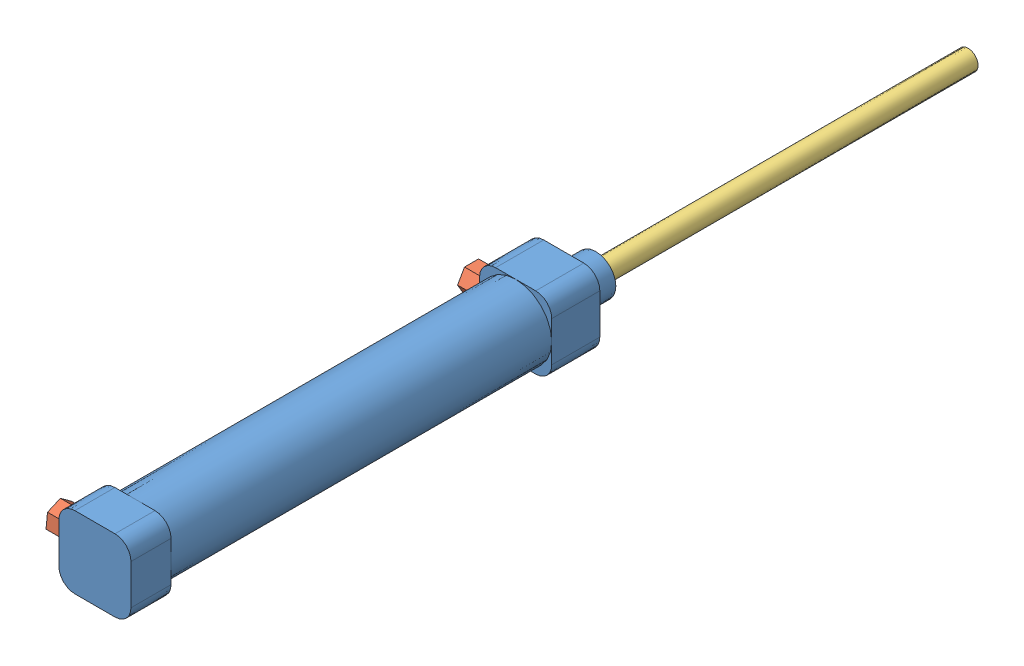
SolidWorks assembly 2气缸16-75（带铰链）装配体, configuration 默认. Lengths in mm.
Overall size (26.22 22.45 217.89).
4 component instances, 3 part files, 6 mates.
Components (placement in the parent):
- 222.4气缸16-75-1: 222.4气缸16-75 [默认] at (2.6982 -2.5413 -63) size (18 18 125)
- 222.4气缸嘴16-75-1: 222.4气缸嘴16-75 [默认] at (-3.3018 -2.5413 -67) x (0 0 1) z (-1 0 0) size (7 6.07 9)
- 222.4气缸杆16-75-1: 222.4气缸杆16-75 [默认] at (2.6982 -2.5413 -40.8909) x (-0.612502 -0.790469 0) z (0 0 -1) size (16 16 135)
- 222.4气缸嘴16-75-2: 222.4气缸嘴16-75 [默认] at (-3.3018 -2.5413 36) x (0 0.593162 0.805083) z (-1 0 0) size (7 6.07 9)
Mates (geometry in assembly coordinates):
- 同心1: concentric: cylinder of assembly; cylinder of assembly; cylinder of 222.4气缸16-75-1 through (2.6982 -2.5413 -45) axis (0 0 -1) radius 2.5; cylinder of 222.4气缸杆16-75-1 through (2.6982 -2.5413 -175.8909) axis (0 0 1) radius 2.5
- 同心2: concentric: cylinder of assembly; cylinder of assembly; cylinder of 222.4气缸16-75-1 through (-3.3018 -2.5413 -67) axis (-1 0 0) radius 2; cylinder of 222.4气缸嘴16-75-1 through (-6.3018 -2.5413 -67) axis (1 0 0) radius 2
- 重合1: coincident: plane of assembly; plane of assembly; plane of 222.4气缸16-75-1 through (-6.3018 -7.5413 -75) normal (-1 0 0); plane of 222.4气缸嘴16-75-1 through (-6.3018 0.4834 -65.2391) normal (1 0 0)
- 同心3: concentric: cylinder of assembly; cylinder of assembly; cylinder of 222.4气缸16-75-1 through (-3.3018 -2.5413 36) axis (-1 0 0) radius 1.9805; cylinder of 222.4气缸嘴16-75-2 through (-6.3018 -2.5413 36) axis (1 0 0) radius 2
- 重合2: coincident: plane of assembly; plane of assembly; plane of 222.4气缸16-75-1 through (-6.3018 -7.5413 42) normal (-1 0 0); plane of 222.4气缸嘴16-75-2 through (-6.3018 0.9383 35.6235) normal (1 0 0)
- LimitDistance2: limit distance = 100.8909 mm: plane of assembly; plane of assembly; plane of 222.4气缸16-75-1 through (7.6982 -7.5413 -75) normal (0 0 -1); plane of 222.4气缸杆16-75-1 through (2.6982 -2.5413 -175.8909) normal (0 0 -1)
